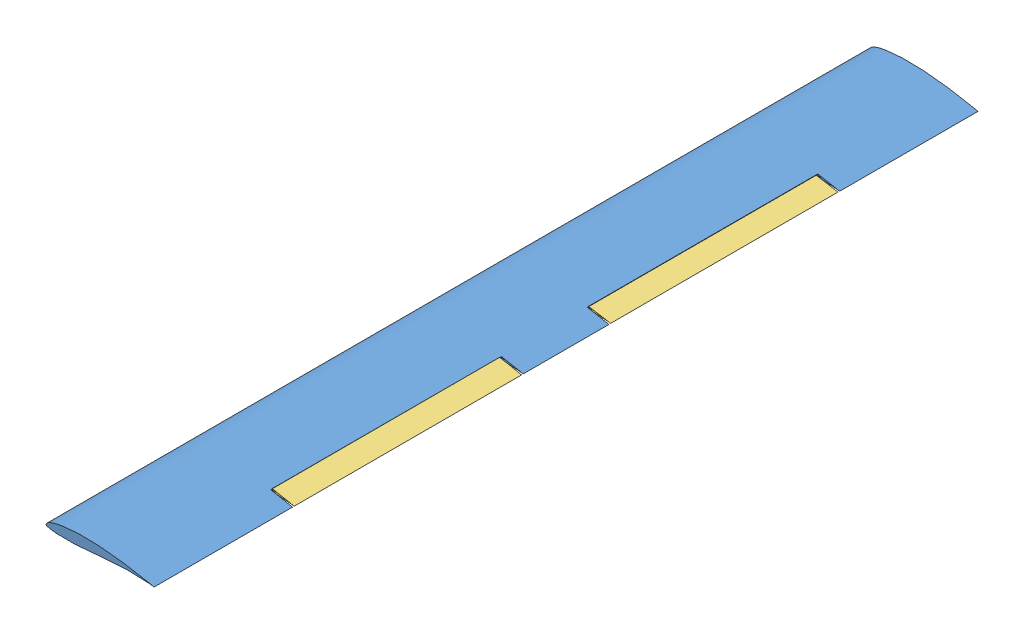
SolidWorks assembly wing assembly, configuration Default. Lengths in mm.
Overall size (164.45 17.08 1250).
5 component instances, 3 part files, 8 mates.
Components (placement in the parent):
- Full wing-2: Full wing [Default] at (-572.4442 1159.0554 -691.5441) size (164.45 17.08 1250)
- flap spar-3: flap spar [Default] at (-438.4442 1163.3033 -17.5441) x (0 0 1) z (-1 0 0) size (380 2 2)
- Flap-3: Flap [Default] at (-567.9103 1160.0213 0.9559) x (0.999979 -0.006499 0) z (0 0 1) size (35.06 6.29 345)
- flap spar-4: flap spar [Default] at (-438.5053 1162.7314 -102.5441) x (0 0 -1) z (1 0 0) size (380 2 2)
- Flap-4: Flap [Default] at (-567.8357 1155.9555 -479.0441) x (0.99979 0.0205 0) z (0 0 1) size (35.06 6.29 345)
Mates (geometry in assembly coordinates):
- Concentric1: concentric aligned: cylinder of Full wing-2 through (-438.4442 1163.3033 -17.5441) axis (0 0 1) radius 1; cylinder of Flap-3 through (-438.4442 1163.3033 0.9559) axis (0 0 1) radius 1
- Concentric2: concentric anti-aligned: cylinder of flap spar-3 through (-438.4442 1163.3033 362.4559) axis (0 0 -1) radius 1; cylinder of Flap-3 through (-438.4442 1163.3033 0.9559) axis (0 0 1) radius 1
- Coincident6: coincident anti-aligned: circle of Full wing-2; circle of flap spar-3
- Coincident9: coincident anti-aligned: cylinder of Full wing-2 through (-438.5053 1162.7314 -501.5441) axis (0 0 1) radius 1; circle of flap spar-4
- Coincident10: coincident aligned: circle of Full wing-2; circle of flap spar-4
- Concentric3: concentric aligned: circle of Full wing-2; circle of Flap-4
- Distance1: distance = 2.5 mm anti-aligned: plane of Full wing-2 through (-408.4442 1269.0554 -131.5441) normal (0 0 -1); plane of Flap-4 through (-567.4091 1157.4676 -134.0441) normal (0 0 1)
- Distance3: distance = 2.5 mm anti-aligned: plane of Full wing-2 through (-408.4442 1269.0554 348.4559) normal (0 0 -1); plane of Flap-3 through (-567.4431 1161.5214 345.9559) normal (0 0 1)
